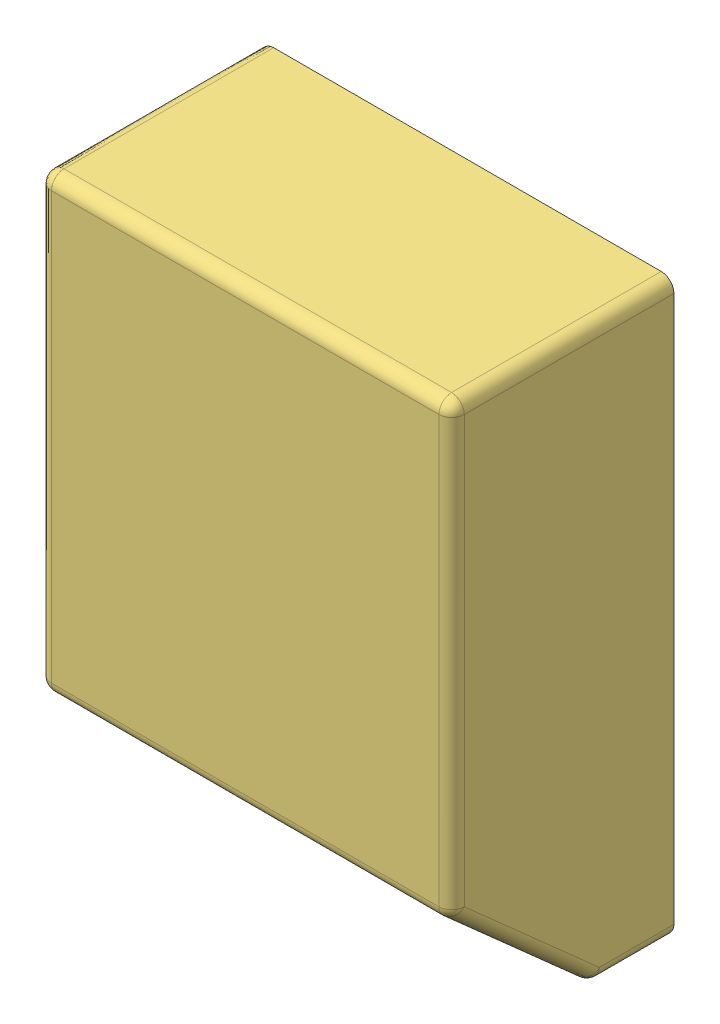
SolidWorks assembly Assem1, configuration Default. Lengths in mm.
Overall size (130 180 70.06).
3 component instances, 3 part files, 6 mates.
Components (placement in the parent):
- JBC_SolderingIron2-1: JBC_SolderingIron2 [Default] at (-50 -73.8156 15.9935) x (1 0 0) z (0 -0.747409 0.664364) size (100 55 34.69)
- Transformer-1: Transformer [Default] at (0 15.4632 6) x (-0.991264 -0.131891 0) z (0 0 -1) size (112 112 54)
- housing-1: housing [Default] at origin size (130 180 70)
Mates (geometry in assembly coordinates):
- Coincident1: coordinate: point of housing-1; point of assembly
- Coincident2: coincident aligned: plane of Transformer-1 through (0 15.4632 0) normal (0 0 -1); plane of housing-1 through (0 0 0) normal (0 0 -1)
- Coincident11: coincident: point of Transformer-1; plane of assembly
- Coincident14: coincident anti-aligned: line of JBC_SolderingIron2-1 through (-43.506 -84.5467 28.8772) axis (1 0 0); line of housing-1 through (25.794 -84.5467 28.8772) axis (-1 0 0)
- Coincident15: coincident anti-aligned: plane of JBC_SolderingIron2-1 through (-1.268 -67.9376 47.5624) normal (0 -0.747409 0.664364); plane of housing-1 through (0 -61.5685 54.7276) normal (0 0.747409 -0.664364)
- Coincident16: coincident anti-aligned: line of JBC_SolderingIron2-1 through (-43.506 -51.3285 66.2476) axis (0 -0.664364 -0.747409); line of housing-1 through (-43.506 -84.5467 28.8772) axis (0 0.664364 0.747409)
